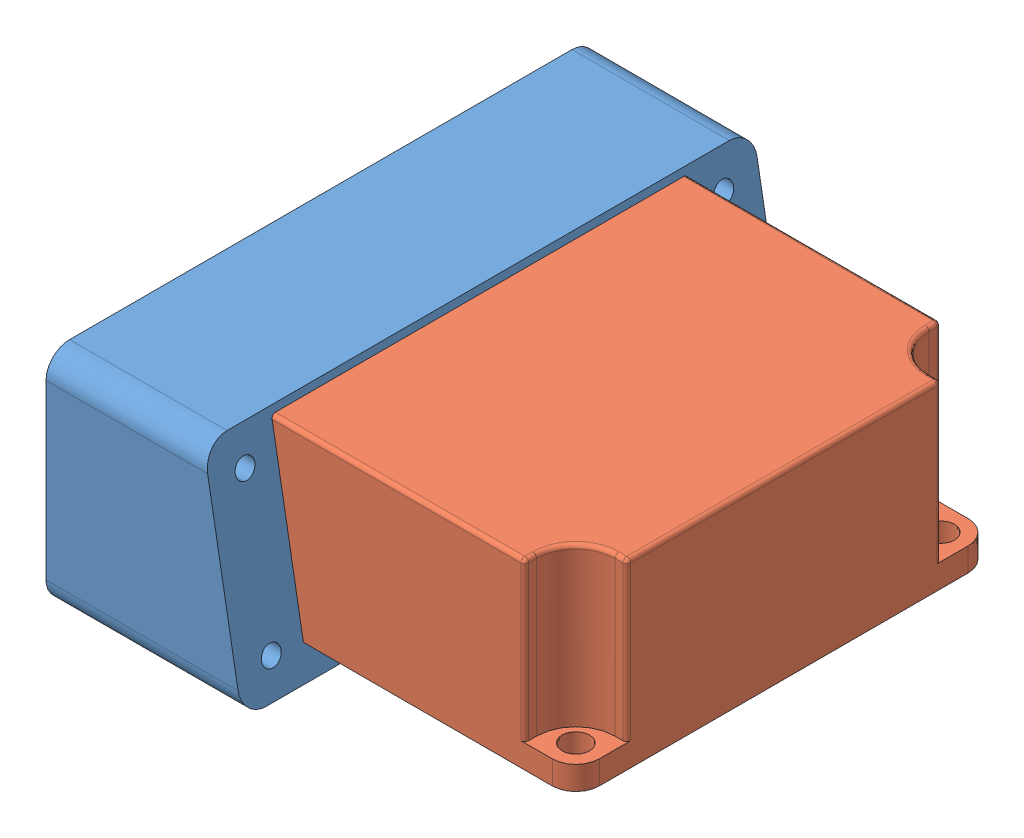
SolidWorks assembly LectorTapa, configuration Default. Lengths in mm.
Overall size (59.01 28.02 70.02).
2 component instances, 2 part files, 3 mates.
Components (placement in the parent):
- TapaLector-1: TapaLector [Default] at (52.7503 36.4867 43.7874) size (25.01 28.02 70.02)
- QR_reader-1: QR_reader [Predeterminado] at (52.7503 36.4867 43.7874) size (49 23.1 53)
Mates (geometry in assembly coordinates):
- Coincident1: coincident: plane of TapaLector-1 through (29.2503 39.4867 70.2874) normal (1 0 0); plane of QR_reader-1 through (29.2503 57.4867 17.2874) normal (-1 0 0)
- Width1: width anti-aligned: plane of TapaLector-1 through (42.2503 35.4867 78.7874) normal (0 0 1); plane of QR_reader-1 through (42.2503 57.4867 8.7874) normal (0 0 -1); plane of TapaLector-1 through (29.2503 39.4867 17.2874) normal (0 0 -1); plane of QR_reader-1 through (29.2503 39.4867 70.2874) normal (0 0 1)
- Width3: width: plane of TapaLector-1 through (27.2503 57.4867 43.7874) normal (0 -1 0); plane of QR_reader-1 through (27.2503 39.4867 43.7874) normal (0 1 0); plane of TapaLector-1; plane of QR_reader-1
